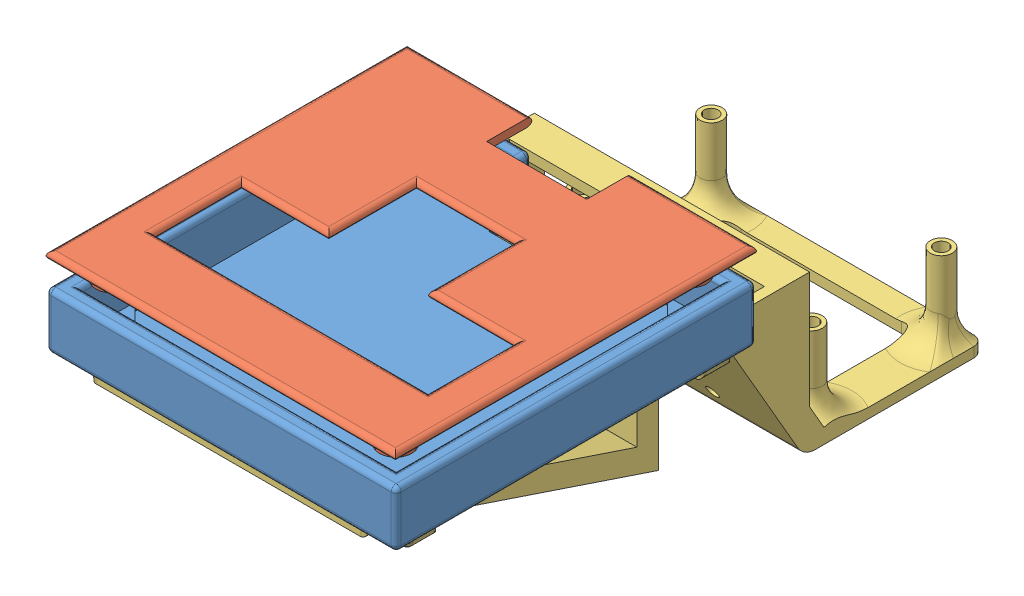
SolidWorks assembly Assem4, configuration Default. Lengths in mm.
Overall size (70.16 48.8 125.18).
3 component instances, 3 part files, 2 mates.
Components (placement in the parent):
- cover-1: cover [Default] at origin size (70 11.2 72)
- cover_top-1: cover_top [Default] at (0.0617 15.8849 0.0601) x (0.999998 0 0.002186) z (-0.002186 0 0.999998) size (70 5 72)
- VCS Holder-1: VCS Holder [30 deg, large cutout] at (-0.0025 -31.3109 -71.452) x (1 0 0) z (0 1 0) size (67.4 123.59 31.31)
Mates (geometry in assembly coordinates):
- Concentric1: concentric anti-aligned: circle of cover-1; circle of VCS Holder-1
- Concentric2: concentric anti-aligned: circle of cover-1; circle of cover_top-1
